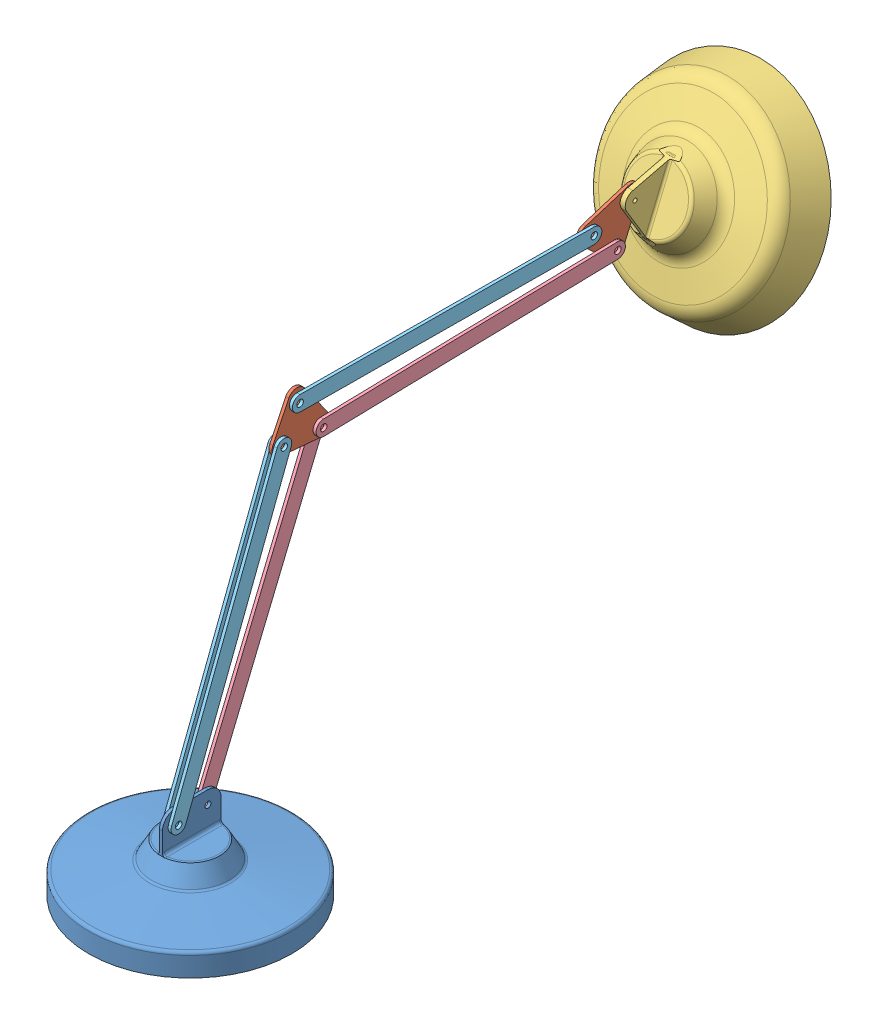
SolidWorks assembly Lamp in elkaar bewegingen, configuration Default. Lengths in mm.
Overall size (205.06 477.37 658.29).
9 component instances, 5 part files, 23 mates.
Components (placement in the parent):
- onderkant-1: onderkant [Default] at (40.2249 68.6549 167.7557) size (200 83 200)
- Tussenstuk-1: Tussenstuk [Default] at (41.7249 406.529 40.7217) x (0 -0.812581 -0.582848) z (0 0.582848 -0.812581) size (62.52 3 49.6)
- Bovenkant-1: Bovenkant [Default] at (44.2249 412.5626 -351.7173) x (0 -0.923293 0.384096) z (-1 0 0) size (202.13 104.53 202.13)
- Strip kort-1: Strip kort [Default] at (35.7249 374.7687 62.0138) x (0 -0.923704 0.383107) z (0 0.383107 0.923704) size (305 3 15)
- Strip lang-1: Strip lang [Default] at (35.7249 377.0488 100.1199) x (0 -0.933459 0.358683) z (0 0.358683 0.933459) size (305 3 15)
- Strip kort-3: Strip kort [Default] at (41.7249 419.5845 -211.5578) x (0 -0.022009 0.999758) z (0 0.999758 0.022009) size (305 3 15)
- Strip lang-2: Strip lang [Default] at (44.7249 176.3444 177.2409) x (0 0.933459 -0.358683) z (0 0.358683 0.933459) size (305 3 15)
- Strip lang-3: Strip lang [Default] at (41.7249 444.8379 -188.5147) x (0 0.00671 0.999977) z (0 0.999977 -0.00671) size (305 3 15)
- Tussenstuk-3: Tussenstuk [Default] at (41.7249 448.9934 -264.1445) x (0 0.297673 -0.954668) z (0 0.954668 0.297673) size (62.52 3 49.6)
Mates (geometry in assembly coordinates):
- Concentric19: concentric aligned: cylinder of onderkant-1 through (38.7249 138.6549 183.6885) axis (1 0 0) radius 3; cylinder of Strip lang-2 through (41.7249 138.6549 183.6885) axis (1 0 0) radius 3.25
- Coincident5: coincident anti-aligned: plane of onderkant-1 through (41.7249 138.6549 151.8228) normal (1 0 0); plane of Strip lang-2 through (41.7249 138.6549 183.6885) normal (-1 0 0)
- Concentric20: concentric anti-aligned: cylinder of onderkant-1 through (38.7249 138.6549 183.6885) axis (1 0 0) radius 3; cylinder of Strip lang-1 through (38.7249 138.6549 183.6885) axis (-1 0 0) radius 3.25
- Coincident6: coincident anti-aligned: plane of onderkant-1 through (38.7249 138.6549 151.8228) normal (-1 0 0); plane of Strip lang-1 through (38.7249 409.3581 79.6704) normal (1 0 0)
- Coincident7: coincident anti-aligned: plane of Tussenstuk-1 through (38.7249 441.8643 64.1038) normal (-1 0 0); plane of Strip lang-1 through (38.7249 409.3581 79.6704) normal (1 0 0)
- Concentric21: concentric anti-aligned: cylinder of Tussenstuk-1 through (38.7249 409.3581 79.6704) axis (1 0 0) radius 3; cylinder of Strip lang-1 through (38.7249 409.3581 79.6704) axis (-1 0 0) radius 3.25
- Concentric23: concentric aligned: cylinder of Tussenstuk-1 through (38.7249 409.3581 79.6704) axis (1 0 0) radius 3; cylinder of Strip lang-2 through (41.7249 409.3581 79.6704) axis (1 0 0) radius 3.25
- Concentric24: concentric anti-aligned: cylinder of onderkant-1 through (38.7249 138.6549 151.8228) axis (1 0 0) radius 3; cylinder of Strip kort-1 through (38.7249 138.6549 151.8228) axis (-1 0 0) radius 3.25
- Coincident8: coincident anti-aligned: plane of onderkant-1 through (38.7249 138.6549 151.8228) normal (-1 0 0); plane of Strip kort-1 through (38.7249 406.529 40.7217) normal (1 0 0)
- Concentric25: concentric anti-aligned: cylinder of Tussenstuk-1 through (38.7249 406.529 40.7217) axis (1 0 0) radius 3; cylinder of Strip kort-1 through (38.7249 406.529 40.7217) axis (-1 0 0) radius 3.25
- Concentric26: concentric anti-aligned: cylinder of Tussenstuk-1 through (38.7249 406.529 40.7217) axis (1 0 0) radius 3; cylinder of Strip kort-3 through (44.7249 406.529 40.7217) axis (-1 0 0) radius 3.25
- Coincident9: coincident anti-aligned: plane of Tussenstuk-1 through (41.7249 441.8643 64.1038) normal (1 0 0); plane of Strip kort-3 through (41.7249 412.9115 -249.208) normal (-1 0 0)
- Concentric35: concentric anti-aligned: cylinder of Tussenstuk-1 through (38.7249 439.0322 64.0357) axis (1 0 0) radius 3; cylinder of Strip lang-3 through (44.7249 439.0322 64.0357) axis (-1 0 0) radius 3.25
- Coincident18: coincident anti-aligned: plane of Tussenstuk-1 through (41.7249 441.8643 64.1038) normal (1 0 0); plane of Strip lang-3 through (41.7249 437.0865 -225.9578) normal (-1 0 0)
- Concentric38: concentric anti-aligned: cylinder of Bovenkant-1 through (45.7249 448.9934 -264.1445) axis (-1 0 0) radius 2; cylinder of Tussenstuk-3 through (38.7249 448.9934 -264.1445) axis (1 0 0) radius 3
- Coincident19: coincident anti-aligned: plane of Bovenkant-1 through (41.7249 448.873 -264.4339) normal (-1 0 0); plane of Tussenstuk-3 through (41.7249 437.9126 -223.248) normal (1 0 0)
- Concentric39: concentric anti-aligned: cylinder of Strip kort-3 through (44.7249 412.9115 -249.208) axis (-1 0 0) radius 3.25; cylinder of Tussenstuk-3 through (38.7249 412.9115 -249.208) axis (1 0 0) radius 3
- Coincident20: coincident anti-aligned: plane of Strip kort-3 through (41.7249 412.9115 -249.208) normal (-1 0 0); plane of Tussenstuk-3 through (41.7249 437.9126 -223.248) normal (1 0 0)
- Concentric40: concentric anti-aligned: cylinder of Strip lang-3 through (44.7249 437.0865 -225.9578) axis (-1 0 0) radius 3.25; cylinder of Tussenstuk-3 through (38.7249 437.0865 -225.9578) axis (1 0 0) radius 3
- LimitDistance1: limit distance = 17.3492 mm: plane of Strip lang-3 through (44.7249 429.5866 -225.9075) normal (0 -0.999977 0.00671); line of Strip kort-3 through (44.7249 414.0272 40.8868) axis (-1 0 0)
- LimitDistance3: limit distance = 9.6839 mm: plane of Strip kort-3 through (44.7249 414.0272 40.8868) normal (0 0.999758 0.022009); line of Strip lang-3 through (44.7249 429.5866 -225.9075) axis (-1 0 0)
- LimitAngle3: limit planar angle = 2.774736 rad anti-aligned: plane of Strip lang-2 through (41.7249 412.0482 86.6713) normal (0 0.358683 0.933459); plane of onderkant-1 through (38.7249 116.8193 196.6885) normal (0 0 1)
- LimitDistance4: limit distance = 14.1349 mm: plane of Bovenkant-1 through (45.7249 443.6994 -255.8762) normal (0 -0.517363 0.855766); cylinder of Strip kort-3 through (44.7249 412.9115 -249.208) axis (-1 0 0) radius 7.5
